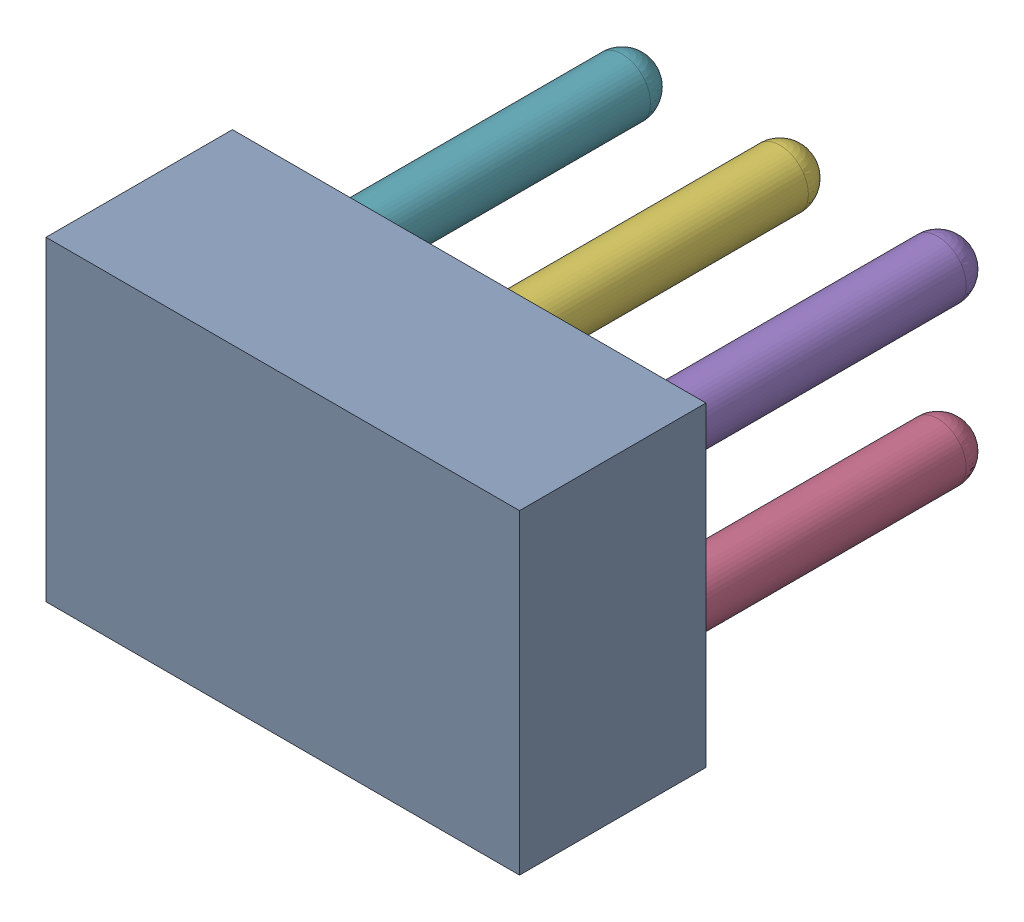
SolidWorks assembly ICSP1, configuration Défaut. Lengths in mm.
Overall size (7.62 5.08 8.46).
8 component instances, 7 part files, 0 mates.
Components (placement in the parent):
- Open CASCADE STEP translator 6.8 1.8.1-1: Open CASCADE STEP translator 6.8 1.8.1 [Défaut] at origin size (7.62 5.08 8.46)
  - Body_1_5-1: Body_1_5 [Défaut] at origin size (7.62 5.08 3)
  - Pin_1_2-1: Pin_1_2 [Défaut] x (0 -1 0) z (0 0 1) size (0.92 0.92 7.42)
  - Pin_2_2-1: Pin_2_2 [Défaut] at (2.54 2.54 0) x (0 -1 0) z (0 0 1) size (0.92 0.92 7.42)
  - Pin_3-1: Pin_3 [Défaut] at (5.08 5.08 0) x (0 -1 0) z (0 0 1) size (0.92 0.92 7.42)
  - Pin_4-1: Pin_4 [Défaut] at (2.54 7.62 0) x (0 -1 0) z (0 0 1) size (0.92 0.92 7.42)
  - Pin_5-1: Pin_5 [Défaut] at (0 5.08 0) x (0 -1 0) z (0 0 1) size (0.92 0.92 7.42)
  - Pin_6-1: Pin_6 [Défaut] at (-2.54 2.54 0) x (0 -1 0) z (0 0 1) size (0.92 0.92 7.42)
